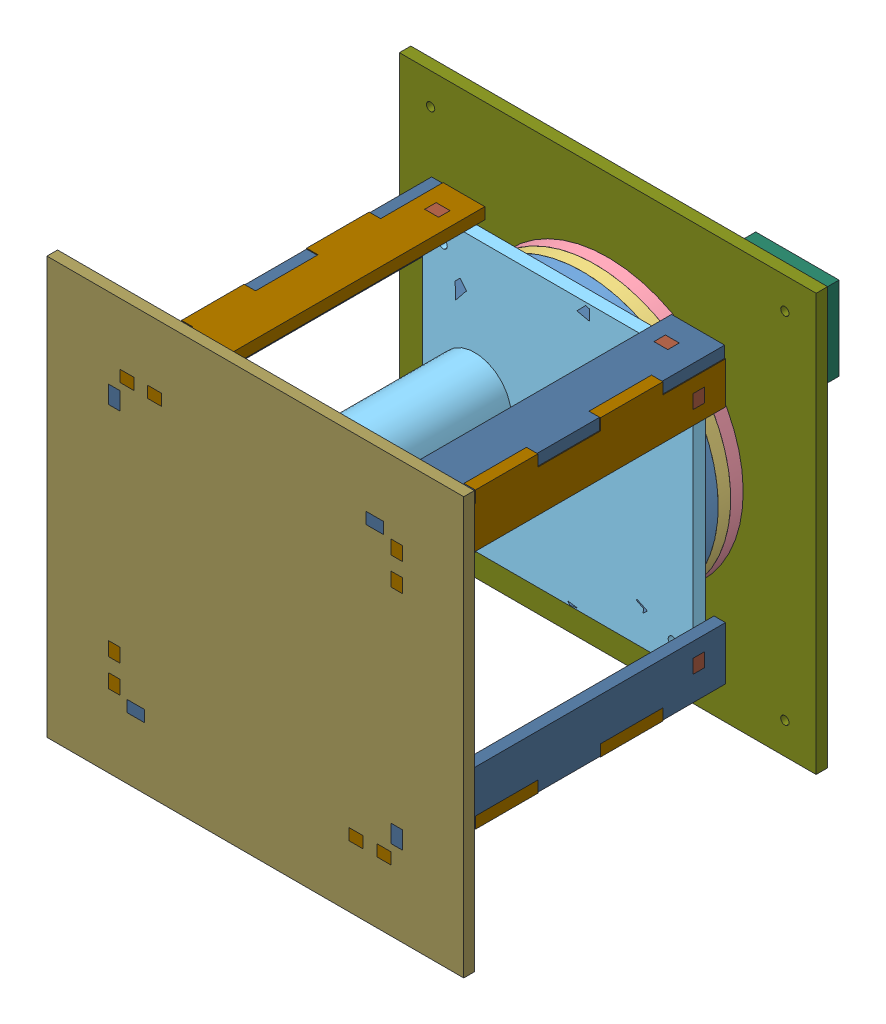
SolidWorks assembly hobby motor air spinner, configuration Default. Lengths in mm.
Overall size (200 200 260.1).
36 component instances, 16 part files, 37 mates.
Components (placement in the parent):
- v4-1: v4 [Default] at (28.7206 104.7701 72.5207) size (168.34 168.34 133.25)
  - middle_ring_outer-1: middle_ring_outer [Default] at (-44.2635 -92.51 -38.9874) x (0.998848 -0.047991 0) z (0 0 1) size (130 130 6)
  - middle_ring_inner-1: middle_ring_inner [Default] at (-44.2635 -92.51 -38.9874) size (40 40 6)
  - top-1: top [Default] at (-44.2635 -92.51 -44.9874) size (130 130 6)
  - floater_top-1: floater_top [Default] at (-44.2635 -92.51 -44.9874) x (-0.363238 -0.931696 0) z (0 0 -1) size (130 130 6)
  - square base-1: square base [Default] at (-44.2635 -92.51 -32.9874) size (130 130 100)
  - midlle_ring_inner_hollow-1: midlle_ring_inner_hollow [Default] at (-44.2635 -92.51 -44.9874) size (27 27 6)
  - floater_lat_stabilizer-2: floater_lat_stabilizer [Default] at (-44.2635 -92.51 -38.9874) size (27 27 6)
  - floater_lat_stabilizer-3: floater_lat_stabilizer [Default] at (-44.2635 -92.51 -32.9874) size (27 27 6)
  - middle_ring_outer-3: middle_ring_outer [Default] at (-44.2635 -92.51 -32.9874) size (130 130 6)
  - middle_ring_inner-2: middle_ring_inner [Default] at (-44.2635 -92.51 -32.9874) size (40 40 6)
  - flip side stabilizer fat-1: flip side stabilizer fat [Default] at (-44.2635 -92.51 -66.2374) size (29.5 29.5 15.25)
- Assem3^hobby motor air spinner-1: Assem3^hobby motor air spinner [Default] at (174.993 123.5066 -22.8427) x (0 -1 0) z (1 0 0) size (25.5 155.1 25.9) (virtual)
  - leg male-1: leg male [Default] at (46.2465 -208.376 -125.5359) size (25.5 155.1 5.5)
  - leg female-1: leg female [Default] at (46.2465 -58.376 -120.4359) x (0 0 -1) z (-1 0 0) size (25.5 155.1 5.5)
  - platform holder-1: platform holder [Default] at (46.2465 -68.376 -125.5359) x (0 0 -1) z (0 -1 0) size (25.5 25.5 5.5)
- Assem3^hobby motor air spinner-2: Assem3^hobby motor air spinner [Default] at (-206.0788 -98.9865 -22.8427) x (0 1 0) z (-1 0 0) size (25.5 155.1 25.9) (virtual)
  - leg male-1: leg male [Default] at (46.2465 -208.376 -125.5359) size (25.5 155.1 5.5)
  - leg female-1: leg female [Default] at (46.2465 -58.376 -120.4359) x (0 0 -1) z (-1 0 0) size (25.5 155.1 5.5)
  - platform holder-1: platform holder [Default] at (46.2465 -68.376 -125.5359) x (0 0 -1) z (0 -1 0) size (25.5 25.5 5.5)
- Assem3^hobby motor air spinner-4: Assem3^hobby motor air spinner [Default] at (-126.7895 202.796 -22.8427) x (1 0 0) z (0 1 0) size (25.5 155.1 25.9) (virtual)
  - leg male-1: leg male [Default] at (46.2465 -208.376 -125.5359) size (25.5 155.1 5.5)
  - leg female-1: leg female [Default] at (46.2465 -58.376 -120.4359) x (0 0 -1) z (-1 0 0) size (25.5 155.1 5.5)
  - platform holder-1: platform holder [Default] at (46.2465 -68.376 -125.5359) x (0 0 -1) z (0 -1 0) size (25.5 25.5 5.5)
- Assem3^hobby motor air spinner-5: Assem3^hobby motor air spinner [Default] at (95.7036 -178.2758 -22.8427) x (-1 0 0) z (0 -1 0) size (25.5 155.1 25.9) (virtual)
  - leg male-1: leg male [Default] at (46.2465 -208.376 -125.5359) size (25.5 155.1 5.5)
  - leg female-1: leg female [Default] at (46.2465 -58.376 -120.4359) x (0 0 -1) z (-1 0 0) size (25.5 155.1 5.5)
  - platform holder-1: platform holder [Default] at (46.2465 -68.376 -125.5359) x (0 0 -1) z (0 -1 0) size (25.5 25.5 5.5)
- base-1: base [Default] at (-115.5429 -87.7399 185.5333) size (200 200 5.1)
- motor holder-1: motor holder [Default] at (9.4571 -18.2399 -23.9667) x (-1 0 0) z (0 1 0) size (61 51 5.5)
- motor holder-2: motor holder [Default] at (14.9571 37.2601 -23.9667) x (0 -1 0) z (-1 0 0) size (61 51 5.5)
- motor holder-3: motor holder [Default] at (-40.5429 42.7601 -23.9667) x (1 0 0) z (0 -1 0) size (61 51 5.5)
- motor holder-4: motor holder [Default] at (-46.0429 -12.7399 -23.9667) x (0 1 0) z (1 0 0) size (61 51 5.5)
- motor holder top-1: motor holder top [Default] at (14.9571 -18.2399 -23.9667) x (-1 0 0) z (0 0 -1) size (61 61 5.5)
- motor-1: motor [Default] at (-15.5429 12.2601 -29.4667) x (-1 0 0) z (0 0 -1) size (40 40 60)
- spinning base-1: spinning base [Default] at (-115.5429 -87.7399 16.0333) size (200 200 5.5)
Mates (geometry in assembly coordinates):
- Coincident22: coincident anti-aligned: plane of v4-1/square base-1 through (49.4571 77.2601 45.5333) normal (0 0 1); plane of Assem3^hobby motor air spinner-2/platform holder-1 through (-80.5429 -46.0733 45.5333) normal (0 0 -1)
- Coincident23: coincident anti-aligned: plane of v4-1/square base-1 through (-80.5429 -52.7399 45.5333) normal (-1 0 0); plane of Assem3^hobby motor air spinner-2/leg male-1 through (-80.5429 -52.7399 155.5333) normal (1 0 0)
- Coincident24: coincident: line of v4-1/square base-1 through (-80.5429 -52.7399 45.5333) axis (1 0 0); plane of Assem3^hobby motor air spinner-2/leg female-1 through (-85.6429 -52.7399 185.5333) normal (0 1 0)
- Coincident25: coincident anti-aligned: plane of v4-1/square base-1 through (49.4571 77.2601 45.5333) normal (0 0 1); plane of Assem3^hobby motor air spinner-1/platform holder-1 through (49.4571 70.5934 45.5333) normal (0 0 -1)
- Coincident26: coincident anti-aligned: plane of v4-1/square base-1 through (-80.5429 77.2601 45.5333) normal (0 1 0); plane of Assem3^hobby motor air spinner-1/leg female-1 through (54.5571 77.2601 185.5333) normal (0 -1 0)
- Coincident27: coincident anti-aligned: plane of v4-1/square base-1 through (49.4571 -52.7399 45.5333) normal (1 0 0); plane of Assem3^hobby motor air spinner-1/leg male-1 through (49.4571 77.2601 155.5333) normal (-1 0 0)
- Coincident28: coincident anti-aligned: plane of v4-1/square base-1 through (49.4571 77.2601 45.5333) normal (0 0 1); plane of Assem3^hobby motor air spinner-4/platform holder-1 through (-73.8763 77.2601 45.5333) normal (0 0 -1)
- Coincident29: coincident anti-aligned: plane of v4-1/square base-1 through (49.4571 77.2601 45.5333) normal (0 0 1); plane of Assem3^hobby motor air spinner-4/platform holder-1 through (-73.8763 77.2601 45.5333) normal (0 0 -1)
- Coincident30: coincident anti-aligned: plane of v4-1/square base-1 through (-80.5429 77.2601 45.5333) normal (0 1 0); plane of Assem3^hobby motor air spinner-4/leg male-1 through (-80.5429 77.2601 155.5333) normal (0 -1 0)
- Coincident31: coincident anti-aligned: plane of v4-1/square base-1 through (-80.5429 -52.7399 45.5333) normal (-1 0 0); plane of Assem3^hobby motor air spinner-4/leg female-1 through (-80.5429 82.3601 185.5333) normal (1 0 0)
- Coincident32: coincident anti-aligned: plane of v4-1/square base-1 through (49.4571 77.2601 45.5333) normal (0 0 1); plane of Assem3^hobby motor air spinner-5/platform holder-1 through (42.7904 -52.7399 45.5333) normal (0 0 -1)
- Coincident33: coincident anti-aligned: plane of v4-1/square base-1 through (49.4571 -52.7399 45.5333) normal (1 0 0); plane of Assem3^hobby motor air spinner-5/leg female-1 through (49.4571 -57.8399 185.5333) normal (-1 0 0)
- Coincident34: coincident anti-aligned: plane of v4-1/square base-1 through (-80.5429 -52.7399 45.5333) normal (0 -1 0); plane of Assem3^hobby motor air spinner-5/leg male-1 through (49.4571 -52.7399 155.5333) normal (0 1 0)
- Width1: width: plane of Assem3^hobby motor air spinner-5/leg male-1 through (49.4571 -58.2399 155.5333) normal (0 -1 0); plane of Assem3^hobby motor air spinner-1/leg female-1 through (54.5571 82.7601 185.5333) normal (0 1 0); plane of base-1 through (-115.5429 112.2601 190.6333) normal (0 1 0); plane of base-1 through (-115.5429 -87.7399 190.6333) normal (0 -1 0)
- Width2: width: plane of Assem3^hobby motor air spinner-5/leg female-1 through (54.9571 -57.8399 185.5333) normal (1 0 0); plane of Assem3^hobby motor air spinner-2/leg male-1 through (-86.0429 -52.7399 155.5333) normal (-1 0 0); plane of base-1 through (84.4571 -87.7399 190.6333) normal (1 0 0); plane of base-1 through (-115.5429 -87.7399 190.6333) normal (-1 0 0)
- Coincident35: coincident anti-aligned: plane of Assem3^hobby motor air spinner-2/leg female-1 through (-85.6429 -58.2399 185.5333) normal (0 0 1); plane of base-1 through (-115.5429 112.2601 185.5333) normal (0 0 -1)
- Coincident39: coincident aligned: plane of motor holder-1 through (14.9571 -12.7399 -10.6334) normal (1 0 0); plane of motor holder-2 through (14.9571 -12.7399 16.0333) normal (1 0 0)
- Coincident40: coincident aligned: plane of motor holder-1 through (-40.5429 -18.2399 16.0333) normal (0 -1 0); plane of motor holder-2 through (9.4571 -18.2399 2.7) normal (0 -1 0)
- Coincident41: coincident aligned: plane of motor holder-1 through (9.4571 -12.7399 16.0333) normal (0 0 1); plane of motor holder-2 through (9.4571 3.9267 16.0333) normal (0 0 1)
- Coincident42: coincident aligned: plane of motor holder-1 through (-40.5429 -18.2399 16.0333) normal (0 -1 0); plane of motor holder-4 through (-40.5429 -18.2399 -10.6334) normal (0 -1 0)
- Coincident43: coincident anti-aligned: plane of motor holder-1 through (-40.5429 -12.7399 2.7) normal (-1 0 0); plane of motor holder-4 through (-40.5429 37.2601 16.0333) normal (1 0 0)
- Coincident44: coincident aligned: plane of motor holder-1 through (-23.8763 -12.7399 16.0333) normal (0 0 1); plane of motor holder-4 through (-40.5429 -12.7399 16.0333) normal (0 0 1)
- Coincident45: coincident aligned: plane of motor holder-2 through (14.9571 -12.7399 16.0333) normal (1 0 0); plane of motor holder-3 through (14.9571 37.2601 2.7) normal (1 0 0)
- Coincident46: coincident anti-aligned: plane of motor holder-2 through (9.4571 37.2601 2.7) normal (0 1 0); plane of motor holder-3 through (9.4571 37.2601 16.0333) normal (0 -1 0)
- Coincident47: coincident aligned: plane of motor holder-2 through (9.4571 37.2601 16.0333) normal (0 0 1); plane of motor holder-3 through (-40.5429 37.2601 16.0333) normal (0 0 1)
- Coincident48: coincident aligned: plane of motor holder-2 through (14.9571 -12.7399 16.0333) normal (1 0 0); plane of motor holder top-1 through (14.9571 -18.2399 -29.4667) normal (1 0 0)
- Coincident50: coincident aligned: plane of motor holder-3 through (9.4571 42.7601 16.0333) normal (0 1 0); plane of motor holder top-1 through (14.9571 42.7601 -29.4667) normal (0 1 0)
- Coincident51: coincident aligned: plane of motor holder-2 through (9.4571 37.2601 -29.4667) normal (0 0 -1); plane of motor holder top-1 through (14.9571 42.7601 -29.4667) normal (0 0 -1)
- Coincident52: coincident anti-aligned: plane of motor holder top-1 through (14.9571 42.7601 -29.4667) normal (0 0 -1); plane of motor-1 through (-35.5429 32.2601 -29.4667) normal (0 0 1)
- Width3: width: plane of motor-1 through (4.4571 -7.7399 -69.4667) normal (1 0 0); plane of motor-1 through (-35.5429 -7.7399 -69.4667) normal (-1 0 0); plane of motor holder-4 through (-46.0429 37.2601 16.0333) normal (-1 0 0); plane of motor holder-2 through (14.9571 -12.7399 16.0333) normal (1 0 0)
- Width4: width: plane of motor-1 through (4.4571 -7.7399 -69.4667) normal (0 -1 0); plane of motor-1 through (4.4571 32.2601 -69.4667) normal (0 1 0); plane of motor holder-3 through (9.4571 42.7601 16.0333) normal (0 1 0); plane of motor holder-1 through (-40.5429 -18.2399 16.0333) normal (0 -1 0)
- Coincident53: coincident anti-aligned: plane of motor holder-3 through (-7.2096 37.2601 16.0333) normal (0 0 1); plane of spinning base-1 through (-115.5429 112.2601 16.0333) normal (0 0 -1)
- Width5: width: plane of motor holder-2 through (14.9571 -12.7399 16.0333) normal (1 0 0); plane of motor holder-4 through (-46.0429 37.2601 16.0333) normal (-1 0 0); plane of spinning base-1 through (84.4571 -87.7399 21.5333) normal (1 0 0); plane of spinning base-1 through (-115.5429 -87.7399 21.5333) normal (-1 0 0)
- Width6: width: plane of motor holder-3 through (9.4571 42.7601 16.0333) normal (0 1 0); plane of motor holder-1 through (-40.5429 -18.2399 16.0333) normal (0 -1 0); plane of spinning base-1 through (-115.5429 -87.7399 21.5333) normal (0 -1 0); plane of spinning base-1 through (-115.5429 112.2601 21.5333) normal (0 1 0)
- Coincident54: coincident anti-aligned: plane of v4-1/floater_top-1 through (-15.5429 12.2601 21.5333) normal (0 0 -1); plane of spinning base-1 through (-115.5429 112.2601 21.5333) normal (0 0 1)
- Width8: width: plane of spinning base-1 through (84.4571 -87.7399 21.5333) normal (1 0 0); plane of spinning base-1 through (-115.5429 -87.7399 21.5333) normal (-1 0 0); plane of base-1 through (-115.5429 -87.7399 190.6333) normal (-1 0 0); plane of base-1 through (84.4571 -87.7399 190.6333) normal (1 0 0)
- Width9: width: plane of spinning base-1 through (-115.5429 -87.7399 21.5333) normal (0 -1 0); plane of spinning base-1 through (-115.5429 112.2601 21.5333) normal (0 1 0); plane of base-1 through (-115.5429 112.2601 190.6333) normal (0 1 0); plane of base-1 through (-115.5429 -87.7399 190.6333) normal (0 -1 0)
